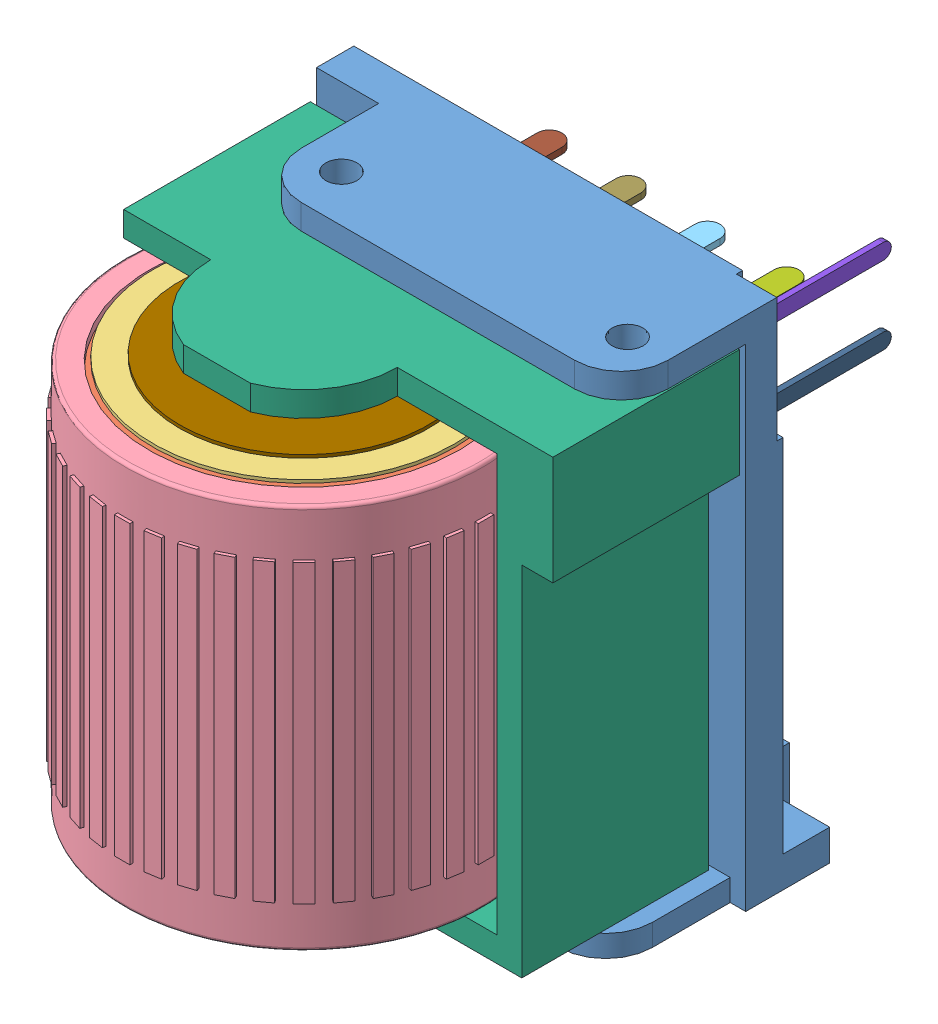
SolidWorks assembly Encoder, configuration Standard. Lengths in mm.
Overall size (13.85 16.6 16.75).
14 component instances, 12 part files, 0 mates.
Components (placement in the parent):
- Encoder.step-1: Encoder.step [Standard] at origin size (13.85 16.6 16.75)
  - RollerEncoder.step-1: RollerEncoder.step [Standard] at (0 0 3.55) x (1 0 0) z (0 -1 0) size (13.85 16.75 16.6)
    - Plastic.step-1: Plastic.step [Standard] at origin size (13.8 7.2 16.6)
    - Barrel in.step-1: Barrel in.step [Standard] at origin size (10 10 11.62)
    - Cap.step-1: Cap.step [Standard] at origin size (9.7 9.7 0.1)
    - Barrel out.step-1: Barrel out.step [Standard] at origin size (11.7 11.69 12.4)
    - Leg (1).step-1: Leg (1).step [Standard] at origin size (0.8 3.7 0.2)
    - housing.step-1: housing.step [Standard] at origin size (13.8 8.8 15)
    - Leg (2).step-1: Leg (2).step [Standard] at origin size (0.8 3.7 0.2)
    - Leg (3).step-1: Leg (3).step [Standard] at origin size (0.18 3.7 0.5)
    - Plastic (1).step-1: Plastic (1).step [Standard] at origin size (8 8.85 0.1)
    - Leg.step-1: Leg.step [Standard] at origin size (0.18 3.7 0.5)
    - Leg (4).step-1: Leg (4).step [Standard] at origin size (0.8 3.7 0.2)
    - Leg (5).step-1: Leg (5).step [Standard] at origin size (0.8 3.7 0.2)
